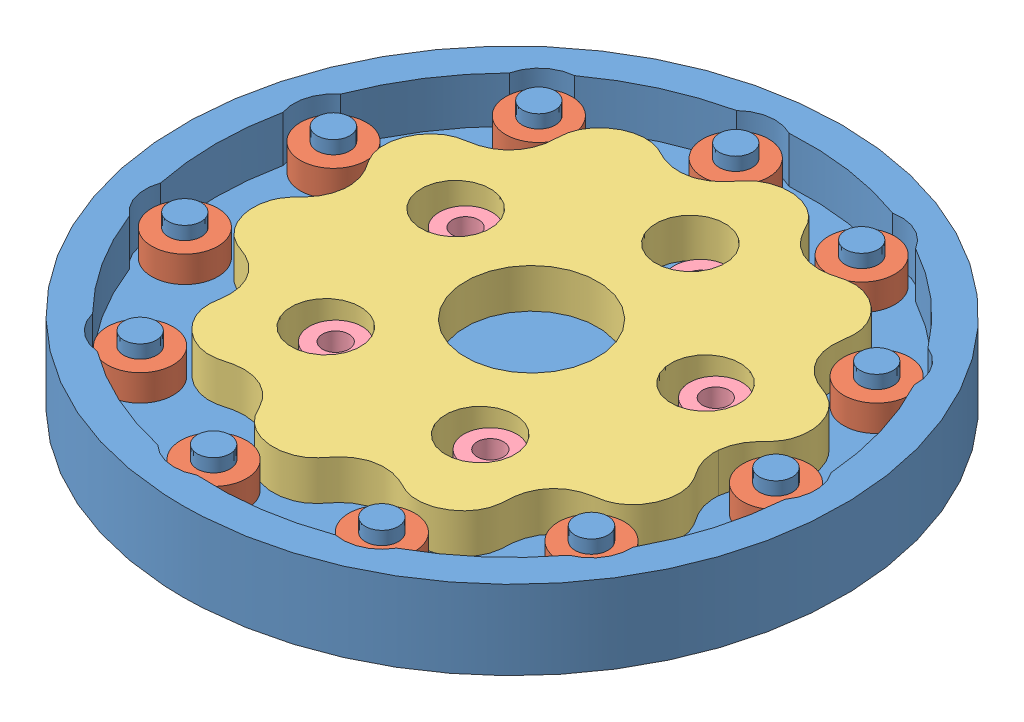
SolidWorks assembly Cycloidal Drive v1.0, configuration Default. Lengths in mm.
Overall size (100 12 100).
25 component instances, 10 part files, 39 mates.
Components (placement in the parent):
- Housing-1: Housing [Default] at origin size (100 12 100)
- 5x10x4-1: 5x10x4 [Default] at (16.6166 6 36.3853) size (10 4 10)
- 5x10x4-2: 5x10x4 [Default] at (-38.3797 6 -11.2693) size (10 4 10)
- 5x10x4-3: 5x10x4 [Default] at (-26.1944 6 -30.23) size (10 4 10)
- 5x10x4-4: 5x10x4 [Default] at (33.6501 6 -21.6256) size (10 4 10)
- 5x10x4-5: 5x10x4 [Default] at (40 6 0) size (10 4 10)
- 5x10x4-6: 5x10x4 [Default] at (-26.1944 6 30.23) size (10 4 10)
- 5x10x4-7: 5x10x4 [Default] at (-5.6926 6 39.5929) size (10 4 10)
- 5x10x4-8: 5x10x4 [Default] at (33.6501 6 21.6256) size (10 4 10)
- 5x10x4-9: 5x10x4 [Default] at (-38.3797 6 11.2693) size (10 4 10)
- 5x10x4-10: 5x10x4 [Default] at (16.6166 6 -36.3853) size (10 4 10)
- 5x10x4-11: 5x10x4 [Default] at (-5.6926 6 -39.5929) size (10 4 10)
- Cycloid v1.0-1: Cycloid v1.0 [Default] at (1.0005 5 -1.9302) x (0.995542 0 0.094322) z (-0.094322 0 0.995542) size (70.23 6 73.05)
- A12 Motor-1: A12 Motor [Default] at (-43.4831 -62.2114 -69.9891) size (114.92 36.5 114.92) (hidden)
  - Rotor-1: Rotor [Default] at (43.4831 60.7114 69.9891) x (0.31946 0 0.9476) z (0.9476 0 -0.31946) size (90.7 27.5 90.7)
  - Shaft-1: Shaft [Default] at (95.9137 0.9 6.4258) x (0.31946 0 0.9476) z (-0.9476 0 0.31946) size (29 32 29)
  - Magnets-1: Magnets [Default] at (-3.6016 -6.4704 0.3207) x (1 0 0) z (0 0 1) size (86.25 13 86.23)
  - Stator-1: Stator [Default] at (43.4831 37.7114 69.9891) x (0.14303 0 -0.989718) z (0.989718 0 0.14303) size (83 13 83)
  - Middle-2: Middle [Default] at (43.4831 37.7114 69.9891) x (-0.14303 0 0.989718) z (0 -1 0) size (58 58 24)
  - Cap-1: Cap [Default] at (95.9137 35.2114 6.4258) x (-0.31946 0 -0.9476) z (0 -1 0) size (16 16 5.5)
- 4x8x3-1: 4x8x3 [Default] at (-18.0683 6 -10.9966) size (8 3 8)
- 4x8x3-2: 4x8x3 [Default] at (4.2839 3.5 -24.294) size (8 3 8)
- 4x8x3-3: 4x8x3 [Default] at (-12.4058 6.5 14.3616) size (8 3 8)
- 4x8x3-4: 4x8x3 [Default] at (13.4552 6.5 16.7698) size (8 3 8)
- 4x8x3-5: 4x8x3 [Default] at (23.7745 6.5 -7.1021) size (8 3 8)
Mates (geometry in assembly coordinates):
- Concentric1: concentric: cylinder of assembly; cylinder of assembly; cylinder of Housing-1 through (16.6166 12 36.3853) axis (0 -1 0) radius 2.5; cylinder of 5x10x4-1 through (16.6166 10 36.3853) axis (0 -1 0) radius 2.5
- Distance1: distance = 5 mm: plane of assembly; plane of assembly; plane of 5x10x4-1 through (16.6166 10 36.3853) normal (0 1 0); plane of Housing-1 through (0 5 0) normal (0 1 0)
- Concentric2: concentric: cylinder of assembly; cylinder of assembly; cylinder of Housing-1 through (-5.6926 12 39.5929) axis (0 -1 0) radius 2.5; cylinder of 5x10x4-7 through (-5.6926 10 39.5929) axis (0 -1 0) radius 2.5
- Distance2: distance = 2 mm: plane of assembly; plane of assembly; plane of 5x10x4-7 through (-5.6926 10 39.5929) normal (0 1 0); plane of Housing-1 through (-5.6926 12 39.5929) normal (0 1 0)
- Concentric3: concentric: cylinder of assembly; cylinder of assembly; cylinder of Housing-1 through (-26.1944 12 30.23) axis (0 -1 0) radius 2.5; cylinder of 5x10x4-6 through (-26.1944 10 30.23) axis (0 -1 0) radius 2.5
- Distance3: distance = 2 mm: plane of assembly; plane of assembly; plane of 5x10x4-6 through (-26.1944 10 30.23) normal (0 1 0); plane of Housing-1 through (-26.1944 12 30.23) normal (0 1 0)
- Concentric4: concentric: cylinder of assembly; circle of assembly; cylinder of Housing-1 through (-38.3797 12 11.2693) axis (0 -1 0) radius 2.5; circle of 5x10x4-9
- Distance4: distance = 2 mm: plane of assembly; plane of assembly; plane of 5x10x4-9 through (-38.3797 10 11.2693) normal (0 1 0); plane of Housing-1 through (-38.3797 12 11.2693) normal (0 1 0)
- Concentric5: concentric: cylinder of assembly; cylinder of assembly; cylinder of Housing-1 through (-38.3797 12 -11.2693) axis (0 -1 0) radius 2.5; cylinder of 5x10x4-2 through (-38.3797 10 -11.2693) axis (0 -1 0) radius 2.5
- Distance5: distance = 1 mm: plane of assembly; plane of assembly; plane of 5x10x4-2 through (-38.3797 6 -11.2693) normal (0 -1 0); plane of Housing-1 through (0 5 0) normal (0 1 0)
- Concentric6: concentric: cylinder of assembly; cylinder of assembly; cylinder of Housing-1 through (33.6501 12 21.6256) axis (0 -1 0) radius 2.5; cylinder of 5x10x4-8 through (33.6501 10 21.6256) axis (0 -1 0) radius 2.5
- Distance6: distance = 1 mm: plane of assembly; plane of assembly; plane of 5x10x4-8 through (33.6501 6 21.6256) normal (0 -1 0); plane of Housing-1 through (0 5 0) normal (0 1 0)
- Concentric7: concentric: cylinder of assembly; cylinder of assembly; cylinder of Housing-1 through (-26.1944 12 -30.23) axis (0 -1 0) radius 2.5; cylinder of 5x10x4-3 through (-26.1944 10 -30.23) axis (0 -1 0) radius 2.5
- Distance7: distance = 1 mm: plane of assembly; plane of assembly; plane of 5x10x4-3 through (-26.1944 6 -30.23) normal (0 -1 0); plane of Housing-1 through (0 5 0) normal (0 1 0)
- Concentric8: concentric: cylinder of assembly; cylinder of assembly; cylinder of Housing-1 through (40 12 0) axis (0 -1 0) radius 2.5; cylinder of 5x10x4-5 through (40 10 0) axis (0 -1 0) radius 2.5
- Distance8: distance = 1 mm: plane of assembly; plane of assembly; plane of 5x10x4-5 through (40 6 0) normal (0 -1 0); plane of Housing-1 through (0 5 0) normal (0 1 0)
- Concentric9: concentric: cylinder of assembly; cylinder of assembly; cylinder of Housing-1 through (33.6501 12 -21.6256) axis (0 -1 0) radius 2.5; cylinder of 5x10x4-4 through (33.6501 10 -21.6256) axis (0 -1 0) radius 2.5
- Distance9: distance = 1 mm: plane of assembly; plane of assembly; plane of 5x10x4-4 through (33.6501 6 -21.6256) normal (0 -1 0); plane of Housing-1 through (0 5 0) normal (0 1 0)
- Concentric10: concentric: cylinder of assembly; cylinder of assembly; cylinder of Housing-1 through (16.6166 12 -36.3853) axis (0 -1 0) radius 2.5; cylinder of 5x10x4-10 through (16.6166 10 -36.3853) axis (0 -1 0) radius 2.5
- Distance10: distance = 1 mm: plane of assembly; plane of assembly; plane of 5x10x4-10 through (16.6166 6 -36.3853) normal (0 -1 0); plane of Housing-1 through (0 5 0) normal (0 1 0)
- Concentric11: concentric: cylinder of assembly; cylinder of assembly; cylinder of Housing-1 through (-5.6926 12 -39.5929) axis (0 -1 0) radius 2.5; cylinder of 5x10x4-11 through (-5.6926 10 -39.5929) axis (0 -1 0) radius 2.5
- Distance11: distance = 1 mm: plane of assembly; plane of assembly; plane of 5x10x4-11 through (-5.6926 6 -39.5929) normal (0 -1 0); plane of Housing-1 through (0 5 0) normal (0 1 0)
- Coincident15: coincident: plane of assembly; plane of assembly; plane of Housing-1 through (0 5 0) normal (0 1 0); plane of Cycloid v1.0-1 through (4.4433 5 -38.2675) normal (0 -1 0)
- Concentric13: concentric: cylinder of assembly; cylinder of assembly; cylinder of Housing-1 through (0 5 0) axis (0 -1 0) radius 50; cylinder of A12 Motor-1/Rotor-1 through (0 -25.5 0) axis (0 1 0) radius 45.35
- Distance13: distance = 5 mm: plane of assembly; plane of assembly; plane of Housing-1 through (0 0 0) normal (0 -1 0); plane of A12 Motor-1/Shaft-1 through (0 5 0) normal (0 1 0)
- InPlace1: in place: plane of ? through (2.7847 11 -36.4936) normal (0 1 0); plane of ? through (0 11 0) normal (0 1 0); moOrthogonalPlaneRef_w of ? through (2.7847 11 -36.4936) normal (0 1 0); plane of ? through (0 11 0) normal (0 0 -1); plane of ? through (2.7847 11 -36.4936) normal (0 1 0); plane of ? through (0 11 0) normal (1 0 0); plane of ? through (2.7847 11 -36.4936) normal (0 1 0); unknown of ?
- Coincident19: coincident: plane of assembly; plane of assembly; plane of Cycloid v1.0-1; plane of ?
- Coincident20: coincident: plane of ? through (2.7847 11 0.0064) normal (0 0 -1); plane of ? through (2.7847 11 0.0064) normal (0 0 -1)
- Coincident21: coincident: plane of ? through (2.7847 11 0.0064) normal (-1 0 0); plane of ? through (2.7847 11 0.0064) normal (1 0 0)
- Distance14: distance = 1.5 mm: plane of assembly; plane of assembly; plane of 4x8x3-3 through (-12.4058 9.5 14.3616) normal (0 1 0); plane of Cycloid v1.0-1 through (4.4433 11 -38.2675) normal (0 1 0)
- Distance15: distance = 1 mm: plane of assembly; plane of assembly; plane of 4x8x3-1 through (-18.0683 6 -10.9966) normal (0 -1 0); plane of Cycloid v1.0-1 through (4.4433 5 -38.2675) normal (0 -1 0)
- Distance16: distance = 1.5 mm: plane of assembly; plane of assembly; plane of 4x8x3-2 through (4.2839 3.5 -24.294) normal (0 -1 0); plane of Cycloid v1.0-1 through (4.4433 5 -38.2675) normal (0 -1 0)
- Distance17: distance = 1.5 mm: plane of assembly; plane of assembly; plane of 4x8x3-5 through (23.7745 6.5 -7.1021) normal (0 -1 0); plane of Cycloid v1.0-1 through (4.4433 5 -38.2675) normal (0 -1 0)
- Distance18: distance = 1.5 mm: plane of assembly; plane of assembly; plane of 4x8x3-4 through (13.4552 6.5 16.7698) normal (0 -1 0); plane of Cycloid v1.0-1 through (4.4433 5 -38.2675) normal (0 -1 0)
- Tangent1: tangent: cylinder of assembly; cylinder of assembly; cylinder of Cycloid v1.0-1 through (22.5757 -4 -6.748) axis (0 1 0) radius 5.25; cylinder of 4x8x3-5 through (23.7745 9.5 -7.1021) axis (0 -1 0) radius 4
- Tangent2: tangent: cylinder of assembly; cylinder of assembly; cylinder of Cycloid v1.0-1 through (12.2496 -4 17.1002) axis (0 1 0) radius 5.25; cylinder of 4x8x3-4 through (13.4552 9.5 16.7698) axis (0 -1 0) radius 4
- Tangent3: tangent: cylinder of assembly; cylinder of assembly; cylinder of Cycloid v1.0-1 through (-13.6223 -4 14.649) axis (0 1 0) radius 5.25; cylinder of 4x8x3-3 through (-12.4058 9.5 14.3616) axis (0 -1 0) radius 4
- Tangent4: tangent: cylinder of assembly; cylinder of assembly; cylinder of Cycloid v1.0-1 through (3.0856 -4 -23.9382) axis (0 1 0) radius 5.25; cylinder of 4x8x3-2 through (4.2839 6.5 -24.294) axis (0 -1 0) radius 4
- Tangent5: tangent: cylinder of assembly; cylinder of assembly; cylinder of Cycloid v1.0-1 through (-19.286 -4 -10.7141) axis (0 1 0) radius 5.25; cylinder of 4x8x3-1 through (-18.0683 9 -10.9966) axis (0 -1 0) radius 4
